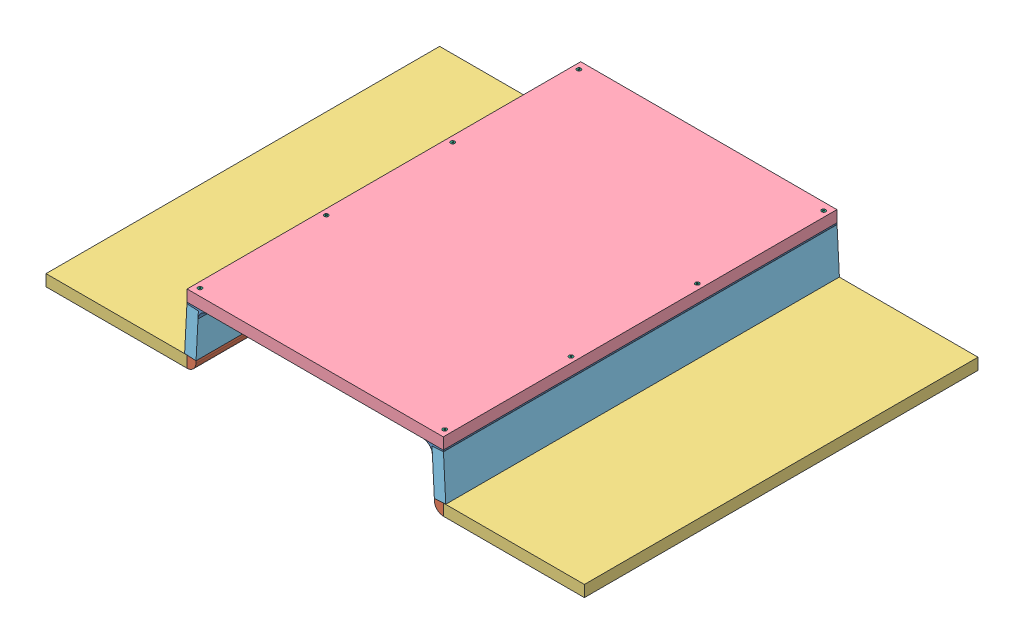
SolidWorks assembly Female mold, configuration Default. Lengths in mm.
Overall size (752.28 96 550).
17 component instances, 6 part files, 30 mates.
Components (placement in the parent):
- A1-1: A1 [Default] at (542.1283 143.3416 262.4919) x (1 0 0) z (0 0 -1) size (28.69 12.79 550)
- A1-2: A1 [Default] at (241.5754 143.3416 -287.5081) x (-1 0 0) z (0 0 1) size (28.69 12.79 550)
- A2-1: A2 [Default] at (212.711 75.8416 262.4919) x (-1 0 0) z (0 0 -1) size (12.66 15.98 550)
- A2-2: A2 [Default] at (570.9927 75.8416 -287.5081) size (12.66 15.98 550)
- P1-1: P1 [Default] at (114.211 63.3416 -12.5081) x (1 0 0) z (0 1 0) size (197 550 16)
- P1-2: P1 [Default] at (669.4927 63.3416 -12.5081) x (1 0 0) z (0 1 0) size (197 550 16)
- P2-1: P2 [Default] at (391.8504 143.3416 -12.5081) x (1 0 0) z (0 1 0) size (357.94 550 16)
- P3-1: P3 [Default] at (556.7069 109.5893 -12.5081) x (0 0 -1) z (0.99863 0.052336 0) size (550 61.94 16)
- P3-2: P3 [Default] at (226.9968 109.5893 -12.5081) x (0 0 -1) z (-0.99863 0.052336 0) size (550 61.94 16)
- 90031A117_Phillips Flat Head Screws for Wood-1: 90031A117_Phillips Flat Head Screws for Wood [90031A117] at (220.8804 143.4666 252.4919) x (0 -1 0) z (0.999698 0 -0.024591) size (31.75 5.71 5.71)
- 90031A117_Phillips Flat Head Screws for Wood-2: 90031A117_Phillips Flat Head Screws for Wood [90031A117] at (220.8804 143.4666 75.9919) x (0 -1 0) z (0.999698 0 -0.024591) size (31.75 5.71 5.71)
- 90031A117_Phillips Flat Head Screws for Wood-3: 90031A117_Phillips Flat Head Screws for Wood [90031A117] at (220.8804 143.4666 -100.5081) x (0 -1 0) z (0.981484 0 -0.191546) size (31.75 5.71 5.71)
- 90031A117_Phillips Flat Head Screws for Wood-4: 90031A117_Phillips Flat Head Screws for Wood [90031A117] at (220.8804 143.4666 -277.0081) x (0 -1 0) z (-0.266658 0 -0.963791) size (31.75 5.71 5.71)
- 90031A117_Phillips Flat Head Screws for Wood-5: 90031A117_Phillips Flat Head Screws for Wood [90031A117] at (562.8204 143.4666 252.4919) x (0 -1 0) z (0.981484 0 -0.191546) size (31.75 5.71 5.71)
- 90031A117_Phillips Flat Head Screws for Wood-6: 90031A117_Phillips Flat Head Screws for Wood [90031A117] at (562.8204 143.4666 75.9919) x (0 -1 0) z (0.981484 0 -0.191546) size (31.75 5.71 5.71)
- 90031A117_Phillips Flat Head Screws for Wood-7: 90031A117_Phillips Flat Head Screws for Wood [90031A117] at (562.8204 143.4666 -100.5081) x (0 -1 0) z (0.981484 0 -0.191546) size (31.75 5.71 5.71)
- 90031A117_Phillips Flat Head Screws for Wood-8: 90031A117_Phillips Flat Head Screws for Wood [90031A117] at (562.8204 143.4666 -277.0081) x (0 -1 0) z (0.981484 0 -0.191546) size (31.75 5.71 5.71)
Mates (geometry in assembly coordinates):
- Coincident31: coincident aligned: plane of P1-1 through (15.711 79.3416 -287.5081) normal (0 0 -1); plane of A2-1 through (212.711 75.8416 -287.5081) normal (0 0 -1)
- Coincident33: coincident anti-aligned: plane of P1-1 through (212.711 79.3416 -287.5081) normal (1 0 0); plane of A2-1 through (212.711 79.3263 -287.5081) normal (-1 0 0)
- Coincident16: coincident aligned: plane of P1-2 through (570.9927 79.3416 -287.5081) normal (0 0 -1); plane of P3-1 through (571.0641 141.3542 -287.5081) normal (0 0 -1)
- Coincident35: coincident anti-aligned: plane of P1-2 through (570.9927 79.3416 -287.5081) normal (-1 0 0); plane of A2-2 through (570.9927 79.3263 262.4919) normal (1 0 0)
- Coincident21: coincident anti-aligned: plane of P2-1 through (391.8504 143.3416 -12.5081) normal (0 -1 0); plane of A1-1 through (542.1283 143.3416 -287.5081) normal (0 1 0)
- Coincident22: coincident aligned: plane of P2-1 through (212.8804 159.3416 262.4919) normal (0 0 1); plane of A1-1 through (542.127 129.8416 262.4919) normal (0 0 1)
- Coincident24: coincident aligned: plane of P2-1 through (212.8804 159.3416 262.4919) normal (0 0 1); plane of P3-1 through (571.0641 141.3542 262.4919) normal (0 0 1)
- Coincident25: coincident anti-aligned: plane of P2-1 through (391.8504 143.3416 -12.5081) normal (0 -1 0); plane of A1-2 through (241.5754 143.3416 262.4919) normal (0 1 0)
- Coincident26: coincident aligned: plane of P2-1 through (212.8804 159.3416 262.4919) normal (0 0 1); plane of A1-2 through (241.5767 129.8416 262.4919) normal (0 0 1)
- Coincident29: coincident aligned: plane of P2-1 through (212.8804 159.3416 -287.5081) normal (0 0 -1); plane of P3-2 through (209.3979 79.4991 -287.5081) normal (0 0 -1)
- Coincident36: coincident anti-aligned: line of P2-1 through (212.8804 143.3416 -287.5081) axis (0 0 1); line of A1-2 through (212.8804 143.3416 262.4919) axis (0 0 -1)
- Concentric9: concentric aligned: cylinder of P2-1 through (220.8804 159.3416 252.4919) axis (0 1 0) radius 1.632; axis of 90031A117_Phillips Flat Head Screws for Wood-1 through (220.8804 148.6736 252.4919) axis (0 1 0)
- Coincident38: coincident aligned: plane of P2-1 through (391.8504 159.3416 -12.5081) normal (0 1 0); plane of 90031A117_Phillips Flat Head Screws for Wood-1 through (220.8804 159.3416 252.4919) normal (0 1 0)
- Concentric10: concentric aligned: cylinder of P2-1 through (220.8804 159.3416 75.9919) axis (0 1 0) radius 1.632; cylinder of 90031A117_Phillips Flat Head Screws for Wood-2 through (220.8804 159.3416 75.9919) axis (0 1 0) radius 1.4224
- Coincident39: coincident aligned: plane of P2-1 through (391.8504 159.3416 -12.5081) normal (0 1 0); plane of 90031A117_Phillips Flat Head Screws for Wood-2 through (220.8804 159.3416 75.9919) normal (0 1 0)
- Concentric11: concentric aligned: cylinder of P2-1 through (220.8804 159.3416 -100.5081) axis (0 1 0) radius 1.632; cylinder of 90031A117_Phillips Flat Head Screws for Wood-3 through (220.8804 159.3416 -100.5081) axis (0 1 0) radius 1.4224
- Coincident40: coincident aligned: plane of P2-1 through (391.8504 159.3416 -12.5081) normal (0 1 0); plane of 90031A117_Phillips Flat Head Screws for Wood-3 through (220.8804 159.3416 -100.5081) normal (0 1 0)
- Coincident41: coincident aligned: circle of P2-1; circle of 90031A117_Phillips Flat Head Screws for Wood-4
- Coincident42: coincident aligned: plane of P2-1 through (391.8504 159.3416 -12.5081) normal (0 1 0); plane of 90031A117_Phillips Flat Head Screws for Wood-4 through (220.8804 159.3416 -277.0081) normal (0 1 0)
- Concentric12: concentric aligned: circle of P2-1; cylinder of 90031A117_Phillips Flat Head Screws for Wood-5 through (562.8204 159.3416 252.4919) axis (0 1 0) radius 1.4224
- Coincident43: coincident aligned: plane of P2-1 through (391.8504 159.3416 -12.5081) normal (0 1 0); plane of 90031A117_Phillips Flat Head Screws for Wood-5 through (562.8204 159.3416 252.4919) normal (0 1 0)
- Concentric13: concentric aligned: circle of P2-1; cylinder of 90031A117_Phillips Flat Head Screws for Wood-6 through (562.8204 159.3416 75.9919) axis (0 1 0) radius 1.4224
- Coincident44: coincident aligned: plane of P2-1 through (391.8504 159.3416 -12.5081) normal (0 1 0); plane of 90031A117_Phillips Flat Head Screws for Wood-6 through (562.8204 159.3416 75.9919) normal (0 1 0)
- Concentric14: concentric aligned: circle of P2-1; cylinder of 90031A117_Phillips Flat Head Screws for Wood-7 through (562.8204 159.3416 -100.5081) axis (0 1 0) radius 1.4224
- Coincident45: coincident aligned: plane of P2-1 through (391.8504 159.3416 -12.5081) normal (0 1 0); plane of 90031A117_Phillips Flat Head Screws for Wood-7 through (562.8204 159.3416 -100.5081) normal (0 1 0)
- Concentric15: concentric aligned: circle of P2-1; cylinder of 90031A117_Phillips Flat Head Screws for Wood-8 through (562.8204 159.3416 -277.0081) axis (0 1 0) radius 1.4224
- Coincident46: coincident aligned: plane of P2-1 through (391.8504 159.3416 -12.5081) normal (0 1 0); plane of 90031A117_Phillips Flat Head Screws for Wood-8 through (562.8204 159.3416 -277.0081) normal (0 1 0)
- Coincident34: coincident aligned: plane of P3-1 through (571.0641 141.3542 -287.5081) normal (0 0 -1); plane of A2-2 through (570.9927 75.8416 -287.5081) normal (0 0 -1)
- Coincident37: coincident anti-aligned: plane of P3-1 through (571.0641 141.3542 262.4919) normal (-0.052336 0.99863 0); plane of A1-1 through (555.6083 140.5442 -287.5081) normal (0.052336 -0.99863 0)
- Coincident30: coincident anti-aligned: plane of A1-2 through (228.0954 140.5442 262.4919) normal (-0.052336 -0.99863 0); plane of P3-2 through (212.6396 141.3542 262.4919) normal (0.052336 0.99863 0)
